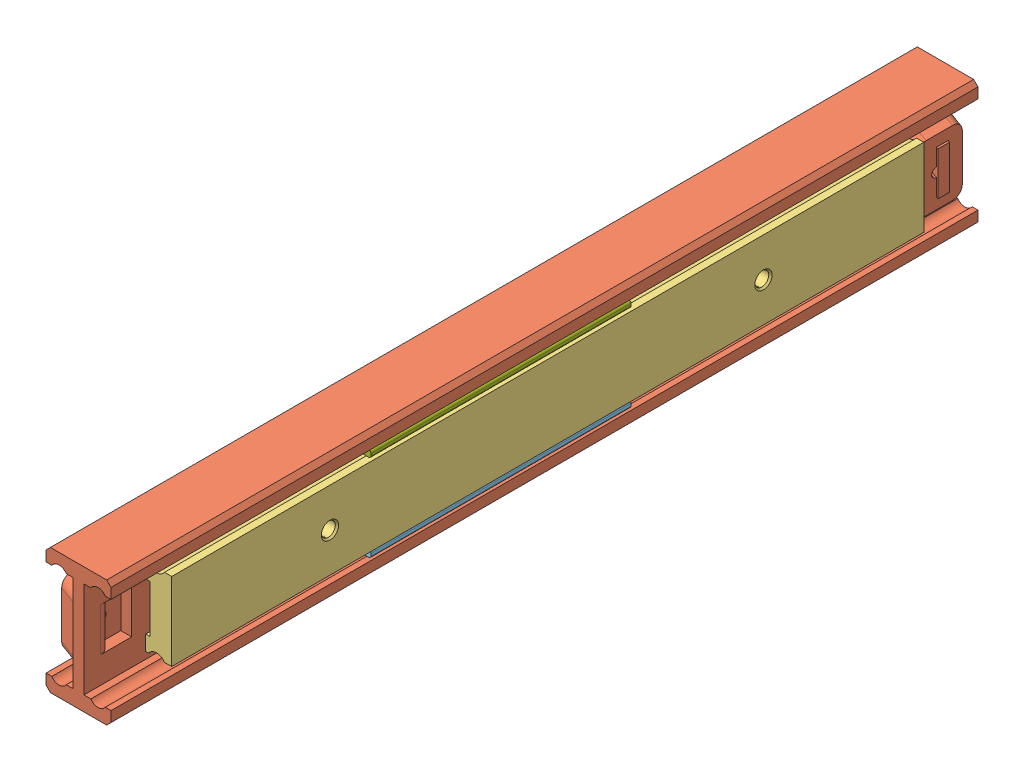
SolidWorks assembly slide-d1422-0200-0, configuration Default. Lengths in mm.
Overall size (16 29 200).
7 component instances, 7 part files, 24 mates.
Components (placement in the parent):
- slide-d1422-0200-0_01-1: slide-d1422-0200-0_01 [Default] at origin size (6 18 173.5)
- slide-d1422-0200-0_02-1: slide-d1422-0200-0_02 [Default] at (0 -0.2 0) size (15 29 200)
- slide-d1422-0200-0_03-1: slide-d1422-0200-0_03 [Default] at origin size (6 18 173.5)
- slide-d1422-0200-0_04-1: slide-d1422-0200-0_04 [Default] at (0 -0.2 -10) size (5.9 4 60)
- slide-d1422-0200-0_05-1: slide-d1422-0200-0_05 [Default] at (0 -0.2 10) size (5.9 4 60)
- slide-d1422-0200-0_06-1: slide-d1422-0200-0_06 [Default] at (0 -0.2 -10) size (5.9 4 60)
- slide-d1422-0200-0_07-1: slide-d1422-0200-0_07 [Default] at (0 -0.2 10) size (5.9 4 60)
Mates (geometry in assembly coordinates):
- Concentric1: concentric: cylinder of slide-d1422-0200-0_02-1 through (3.5 -10.2 186.5) axis (0 0 -1) radius 2; sphere of slide-d1422-0200-0_04-1
- Concentric2: concentric: cylinder of slide-d1422-0200-0_02-1 through (3.5 -10.2 186.5) axis (0 0 -1) radius 2; sphere of slide-d1422-0200-0_04-1
- Parallel1: parallel anti-aligned: plane of slide-d1422-0200-0_02-1 through (0.5 -11.3 186.5) normal (0 1 0); plane of slide-d1422-0200-0_04-1 through (5.95 -10.96 176.5) normal (0 -1 0)
- Parallel2: parallel: plane of slide-d1422-0200-0_02-1 through (1.8297 10.9 186.5) normal (0 -1 0); plane of slide-d1422-0200-0_06-1 through (1.05 10.56 106.5) normal (0 1 0)
- Concentric3: concentric: cylinder of slide-d1422-0200-0_02-1 through (3.5 9.8 186.5) axis (0 0 -1) radius 2; sphere of slide-d1422-0200-0_06-1
- Concentric4: concentric: cylinder of slide-d1422-0200-0_02-1 through (3.5 9.8 186.5) axis (0 0 -1) radius 2; sphere of slide-d1422-0200-0_06-1
- Concentric5: concentric: cylinder of slide-d1422-0200-0_01-1 through (3.5 -10.2 173.5) axis (0 0 -1) radius 2.2; sphere of slide-d1422-0200-0_04-1
- Concentric8: concentric: cylinder of slide-d1422-0200-0_01-1 through (3.5 -10.2 173.5) axis (0 0 -1) radius 2.2; sphere of slide-d1422-0200-0_04-1
- Parallel3: parallel anti-aligned: plane of slide-d1422-0200-0_01-1 through (1.6561 9 173.5) normal (0 1 0); plane of slide-d1422-0200-0_02-1 through (1.8297 10.9 186.5) normal (0 -1 0)
- LimitDistance2: limit distance = 13 mm aligned: plane of slide-d1422-0200-0_01-1 through (3.5 -10.2 173.5) normal (0 0 1); plane of slide-d1422-0200-0_02-1 through (3.5 -10.2 186.5) normal (0 0 1)
- Parallel4: parallel anti-aligned: plane of slide-d1422-0200-0_02-1 through (14.1703 -11.3 186.5) normal (0 1 0); plane of slide-d1422-0200-0_05-1 through (14.95 -10.96 126.5) normal (0 -1 0)
- Concentric9: concentric: cylinder of slide-d1422-0200-0_02-1 through (12.5 -10.2 186.5) axis (0 0 -1) radius 2; sphere of slide-d1422-0200-0_05-1
- Concentric10: concentric: cylinder of slide-d1422-0200-0_02-1 through (12.5 -10.2 186.5) axis (0 0 -1) radius 2; sphere of slide-d1422-0200-0_05-1
- Parallel5: parallel: plane of slide-d1422-0200-0_02-1 through (15.5 10.9 186.5) normal (0 -1 0); plane of slide-d1422-0200-0_07-1 through (10.05 10.56 56.5) normal (0 1 0)
- Concentric11: concentric: cylinder of slide-d1422-0200-0_02-1 through (12.5 9.8 186.5) axis (0 0 -1) radius 2; sphere of slide-d1422-0200-0_07-1
- Concentric12: concentric: cylinder of slide-d1422-0200-0_02-1 through (12.5 9.8 186.5) axis (0 0 -1) radius 2; sphere of slide-d1422-0200-0_07-1
- Parallel7: parallel anti-aligned: plane of slide-d1422-0200-0_02-1 through (15.5 10.9 186.5) normal (0 -1 0); plane of slide-d1422-0200-0_03-1 through (14.3439 9 -0.5) normal (0 1 0)
- Concentric13: concentric: cylinder of slide-d1422-0200-0_03-1 through (12.5 -10.2 -0.5) axis (0 0 1) radius 2.2; sphere of slide-d1422-0200-0_05-1
- Concentric14: concentric: cylinder of slide-d1422-0200-0_03-1 through (12.5 -10.2 -0.5) axis (0 0 1) radius 2.2; sphere of slide-d1422-0200-0_05-1
- LimitDistance3: limit distance = 13 mm aligned: plane of slide-d1422-0200-0_02-1 through (3.5 -10.2 -13.5) normal (0 0 -1); plane of slide-d1422-0200-0_03-1 through (12.5 -10.2 -0.5) normal (0 0 -1)
- LimitDistance4: limit distance = 60 mm aligned: plane of slide-d1422-0200-0_02-1 through (3.5 -10.2 -13.5) normal (0 0 -1); plane of slide-d1422-0200-0_06-1 through (1.05 9.54 46.5) normal (0 0 -1)
- LimitDistance5: limit distance = 60 mm aligned: plane of slide-d1422-0200-0_02-1 through (3.5 -10.2 -13.5) normal (0 0 -1); plane of slide-d1422-0200-0_04-1 through (1.05 -10.46 46.5) normal (0 0 -1)
- LimitDistance6: limit distance = 60 mm aligned: plane of slide-d1422-0200-0_02-1 through (3.5 -10.2 186.5) normal (0 0 1); plane of slide-d1422-0200-0_07-1 through (10.05 9.54 126.5) normal (0 0 1)
- LimitDistance7: limit distance = 60 mm aligned: plane of slide-d1422-0200-0_05-1 through (10.05 -10.46 126.5) normal (0 0 1); plane of slide-d1422-0200-0_02-1 through (3.5 -10.2 186.5) normal (0 0 1)
